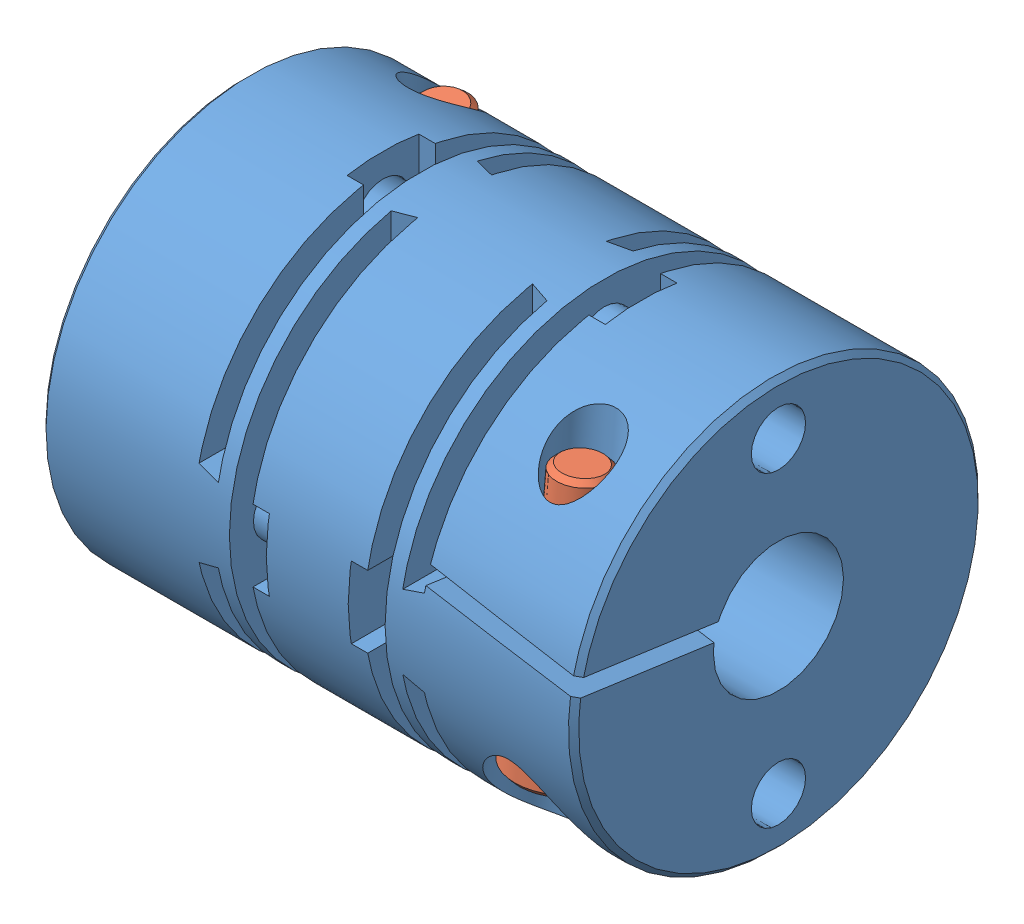
SolidWorks assembly Assem3, configuration Default. Lengths in mm.
Overall size (32.18 20 20).
3 component instances, 2 part files, 0 mates.
Components (placement in the parent):
- Dummy_MCSLC20_6_35_6_35-1: Dummy_MCSLC20_6_35_6_35 [Default] at origin size (26 20 20)
- M2_5x10-1: M2_5x10 [Default] at (3.7 -2.4221 -6.7367) x (0 0.996195 0.087156) z (0 -0.087156 0.996195) size (12.36 4.5 4.5)
- M2_5x10-2: M2_5x10 [Default] at (22.3 -2.4221 6.7367) x (0 0.996195 -0.087156) z (-1 0 0) size (12.36 4.5 4.5)
